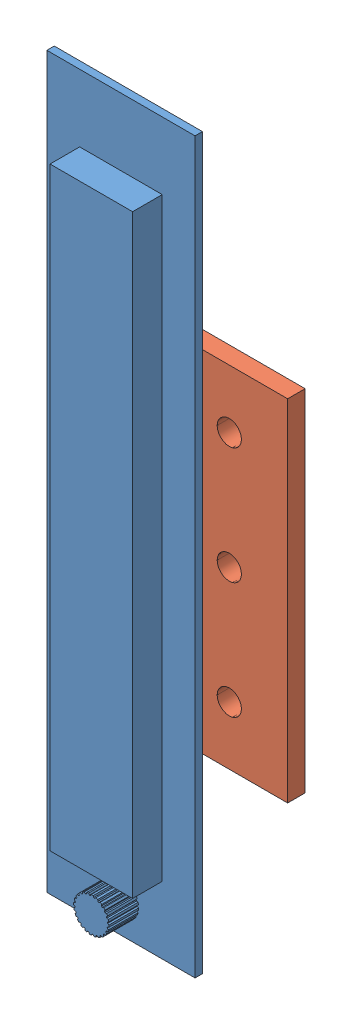
SolidWorks assembly Matheson Trigas Plated Left, configuration Default. Lengths in mm.
Overall size (80 250 18.7).
2 component instances, 2 part files, 3 mates.
Components (placement in the parent):
- Matheson_Tri_Gas-1: Matheson_Tri_Gas [Default] at (86.8459 133.9361 192.9527) size (50.8 250 12.7)
- 40_4366-1: 40_4366 [Default] at (101.4459 74.2136 186.9527) size (80 120 6)
Mates (geometry in assembly coordinates):
- Coincident1: coincident: plane of Matheson_Tri_Gas-1 through (86.8459 133.9361 192.9527) normal (0 0 -1); plane of 40_4366-1 through (101.4459 96.6858 192.9527) normal (0 0 1)
- Coincident2: coincident: plane of Matheson_Tri_Gas-1 through (61.4459 8.9361 195.4927) normal (-1 0 0); plane of 40_4366-1 through (61.4459 216.6858 192.9527) normal (-1 0 0)
- Distance1: distance = 65 mm: line of 40_4366-1 through (141.4459 194.2136 186.9527) axis (-1 0 0); line of Matheson_Tri_Gas-1 through (112.2459 258.9361 192.9527) axis (-1 0 0)
